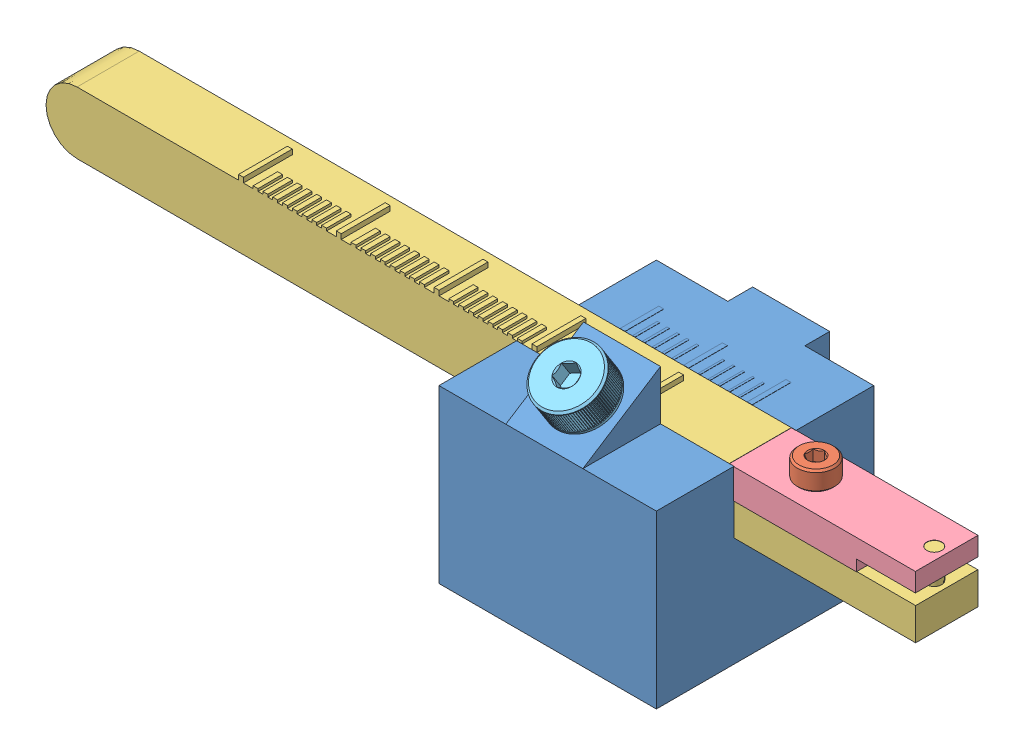
SolidWorks assembly headbar finished assem (1), configuration Default. Lengths in mm.
Overall size (88.9 24.55 25.25).
6 component instances, 5 part files, 4 mates.
Components (placement in the parent):
- bar rest-1: bar rest [Default] at origin size (22.23 22.61 24.77)
- 91292A003_TYPE 18-8 SS SOCKET HEAD CAP SCREW-1: 91292A003_TYPE 18-8 SS SOCKET HEAD CAP SCREW [91292A003] at (27.4332 5.7455 0) x (1 0 0) z (0 -1 0) size (3.8 3.8 5.09)
- headbar-1: headbar [Default] at (89.3465 -57.3797 -49.0764) x (0 0 1) z (-1 0 0) size (6.4 6.86 88.9)
  - headpost holder-1: headpost holder [Default] at (49.0764 62.9677 48.5529) x (0 1 0) z (0 0 1) size (6.86 6.35 88.9)
  - holder piece little-1: holder piece little [Default] at (49.0764 64.2202 58.1033) x (0 0 1) z (-1 0 0) size (19.1 3.05 6.4)
- 96125A301_NICKEL ALLOY SHOULDER SCREW-1: 96125A301_NICKEL ALLOY SHOULDER SCREW [96125A301] at (10.7798 13.9746 8.8593) x (1 0 0) z (0 0.842271 0.539054) size (6.35 6.35 10.69)
Mates (geometry in assembly coordinates):
- Concentric4: concentric anti-aligned: circle of 91292A003_TYPE 18-8 SS SOCKET HEAD CAP SCREW-1; circle of headbar-1/holder piece little-1
- Coincident3: coincident anti-aligned: plane of 91292A003_TYPE 18-8 SS SOCKET HEAD CAP SCREW-1 through (27.4332 8.7455 0) normal (0 -1 0); plane of headbar-1/holder piece little-1 through (31.2432 8.7455 0) normal (0 1 0)
- Concentric5: concentric anti-aligned: cylinder of bar rest-1 through (10.7798 11.3004 7.1478) axis (0 0.842271 0.539054) radius 2.5527; circle of 96125A301_NICKEL ALLOY SHOULDER SCREW-1
- Coincident5: coincident anti-aligned: plane of bar rest-1 through (-0.001 8.763 11.1125) normal (0 0.842271 0.539054); plane of 96125A301_NICKEL ALLOY SHOULDER SCREW-1 through (10.7798 9.5889 9.822) normal (0 -0.842271 -0.539054)
